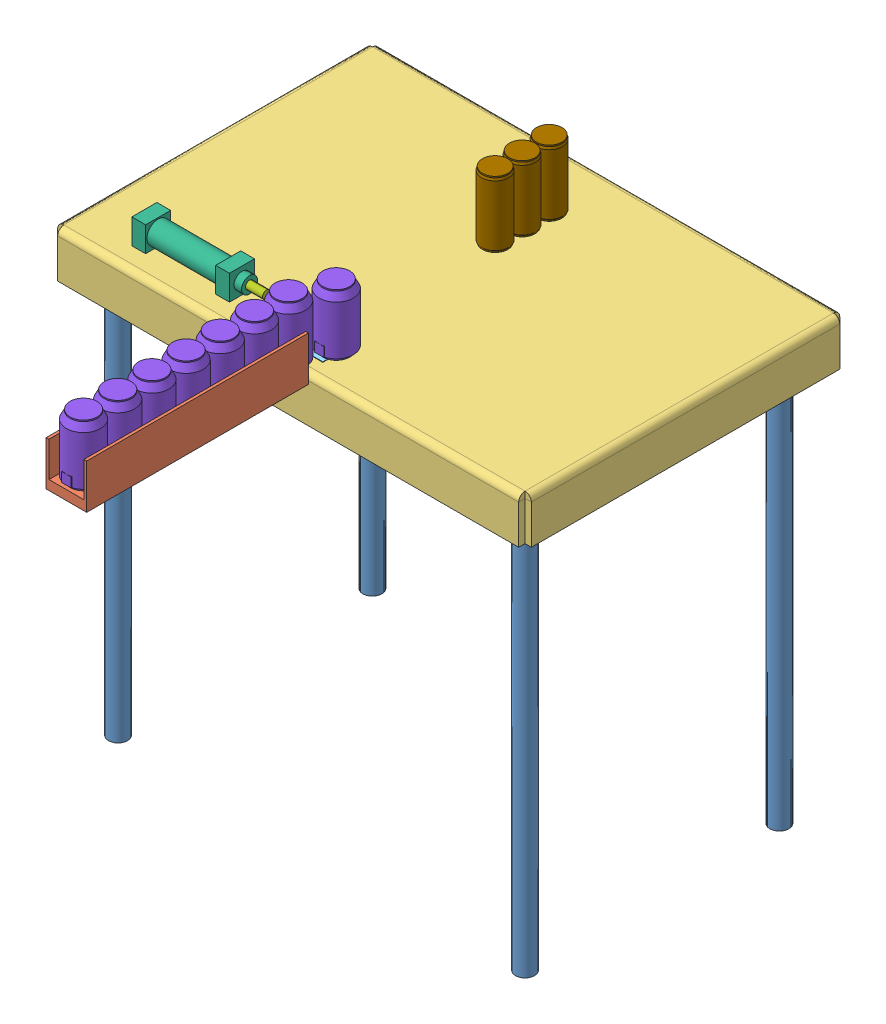
SolidWorks assembly Full_Assembly_v5, configuration Default. Lengths in mm.
Overall size (946.15 1065.21 1084.08).
19 component instances, 9 part files, 59 mates.
Components (placement in the parent):
- M37 Metal Table-1: M37 Metal Table [Default] at (-122.75 340.8931 1031.9817) size (914.4 863.6 609.6)
- Goose Output-1: Goose Output [Default] at (293.9688 417.0931 1047.8567) size (80.96 88.9 442.73)
- Table Topper-1: Table Topper [Default] at (-125.925 345.3431 1035.1567) size (946.15 90.8 641.35)
- Load Cell Assembly-1: Load Cell Assembly [Default] at (309.0555 378.227 899.7114) size (69.85 26.2 103.99)
  - Load Cell and Brace-1: Load Cell and Brace [Default] at (-9.1055 31.7162 92.7424) size (69 14.2 83)
  - scalePlate_v2_234-1: scalePlate_v2_234 [Default] at (-9.5305 57.9162 113.7283) x (0 0 -1) z (-1 0 0) size (69.85 12 69.85)
- Cylinder-1: Cylinder [Default] at (-22.0508 486.1431 953.5147) x (0 0 1) z (1 0 0) size (50 50 210)
- Rod-1: Rod [Default] at (221.9492 461.1431 978.5147) x (0 0.637822 -0.770184) z (0 0.770184 0.637822) size (16 134 16)
- can355mL-1: can355mL [Default] at (334.45 436.1431 1115.1477) x (0 0 -1) z (1 0 0) size (68.26 122.24 68.26)
- can355mL-2: can355mL [Default] at (334.45 436.1431 1251.6727) x (0 0 -1) z (1 0 0) size (68.26 122.24 68.26)
- can355mL-3: can355mL [Default] at (334.45 436.1431 1183.4102) x (0 0 -1) z (1 0 0) size (68.26 122.24 68.26)
- can250mL-1: can250mL [Default] at (334.45 436.1431 634.4892) x (0.234731 0 0.97206) z (-0.97206 0 0.234731) size (53.98 131.76 53.98)
- can250mL-2: can250mL [Default] at (334.45 436.1431 580.5142) x (0.907124 0 -0.420864) z (0.420864 0 0.907124) size (53.98 131.76 53.98)
- can250mL-3: can250mL [Default] at (334.45 436.1431 526.5392) x (0.515444 0 0.856923) z (-0.856923 0 0.515444) size (53.98 131.76 53.98)
- can355mL-7: can355mL [Default] at (334.45 436.1431 1046.8852) x (0 0 -1) z (1 0 0) size (68.26 122.24 68.26)
- can355mL-8: can355mL [Default] at (334.45 436.1431 1456.4602) x (0 0 -1) z (1 0 0) size (68.26 122.24 68.26)
- can355mL-9: can355mL [Default] at (334.45 436.1431 1319.9352) x (0 0 -1) z (1 0 0) size (68.26 122.24 68.26)
- can355mL-10: can355mL [Default] at (334.45 436.1431 1388.1977) x (0 0 -1) z (1 0 0) size (68.26 122.24 68.26)
- can355mL-11: can355mL [Default] at (361.1963 436.1431 978.5147) x (0 0 -1) z (1 0 0) size (68.26 122.24 68.26)
Mates (geometry in assembly coordinates):
- Width1: width aligned: plane of M37 Metal Table-1 through (791.65 366.2931 1031.9817) normal (1 0 0); plane of Table Topper-1 through (-122.75 366.2931 1031.9817) normal (-1 0 0); plane of M37 Metal Table-1 through (807.525 423.4431 1035.1567) normal (1 0 0); plane of Table Topper-1 through (-138.625 423.4431 1035.1567) normal (-1 0 0)
- Width2: width aligned: plane of M37 Metal Table-1 through (-122.75 366.2931 1031.9817) normal (0 0 1); plane of Table Topper-1 through (-122.75 366.2931 422.3817) normal (0 0 -1); plane of M37 Metal Table-1 through (-125.925 423.4431 1047.8567) normal (0 0 1); plane of Table Topper-1 through (-125.925 423.4431 406.5067) normal (0 0 -1)
- Distance1: distance = 863.6 mm aligned: plane of M37 Metal Table-1 through (-122.75 -446.5069 1031.9817) normal (0 -1 0); plane of Goose Output-1 through (374.9313 417.0931 1490.5914) normal (0 -1 0)
- LimitDistance1: limit distance = 432.5938 mm aligned: plane of Goose Output-1 through (374.9313 505.9931 1490.5914) normal (1 0 0); plane of Table Topper-1 through (807.525 423.4431 1035.1567) normal (1 0 0)
- LimitDistance2: limit distance = 432.5938 mm aligned: plane of Table Topper-1 through (-138.625 423.4431 1035.1567) normal (-1 0 0); plane of Goose Output-1 through (293.9688 417.0931 1490.5914) normal (-1 0 0)
- Parallel1: parallel aligned: plane of Goose Output-1 through (299.525 436.1431 1490.5914) normal (0 1 0); plane of Table Topper-1 through (-125.925 436.1431 1035.1567) normal (0 1 0)
- Coincident5: coincident aligned: plane of Goose Output-1 through (299.525 436.1431 1490.5914) normal (0 1 0); plane of Table Topper-1 through (-125.925 436.1431 1035.1567) normal (0 1 0)
- Coincident7: coincident aligned: plane of Table Topper-1 through (-125.925 436.1431 1035.1567) normal (0 1 0); plane of Load Cell Assembly-1/scalePlate_v2_234-1 through (299.525 436.1431 1013.4397) normal (0 1 0)
- Concentric1: concentric anti-aligned: cylinder of Cylinder-1 through (187.9492 461.1431 978.5147) axis (-1 0 0) radius 16; cylinder of Rod-1 through (87.9492 461.1431 978.5147) axis (1 0 0) radius 8
- LimitDistance3: limit distance = 34 mm aligned: plane of Rod-1 through (221.9492 461.1431 978.5147) normal (1 0 0); plane of Cylinder-1 through (187.9492 461.1431 978.5147) normal (1 0 0)
- Parallel2: parallel anti-aligned: plane of Table Topper-1 through (-125.925 423.4431 1047.8567) normal (0 0 1); plane of Cylinder-1 through (172.9492 486.1431 953.5147) normal (0 0 -1)
- Coincident9: coincident anti-aligned: plane of Table Topper-1 through (-125.925 436.1431 1035.1567) normal (0 1 0); plane of Cylinder-1 through (5.4492 436.1431 953.5147) normal (0 -1 0)
- Width3: width anti-aligned: plane of Goose Output-1 through (374.9313 505.9931 1490.5914) normal (1 0 0); plane of Load Cell Assembly-1/scalePlate_v2_234-1 through (293.9688 417.0931 1490.5914) normal (-1 0 0); plane of Goose Output-1 through (299.525 432.1431 1013.4397) normal (-1 0 0); plane of Load Cell Assembly-1/scalePlate_v2_234-1 through (369.375 432.1431 1013.4397) normal (1 0 0)
- Width4: width anti-aligned: plane of Cylinder-1 through (172.9492 486.1431 953.5147) normal (0 0 -1); plane of Load Cell Assembly-1/scalePlate_v2_234-1 through (172.9492 486.1431 1003.5147) normal (0 0 1); plane of Cylinder-1 through (299.525 432.1431 1013.4397) normal (0 0 1); plane of Load Cell Assembly-1/scalePlate_v2_234-1 through (299.525 432.1431 943.5897) normal (0 0 -1)
- Width5: width anti-aligned: plane of Table Topper-1 through (807.525 423.4431 1035.1567) normal (1 0 0); plane of Load Cell Assembly-1/scalePlate_v2_234-1 through (-138.625 423.4431 1035.1567) normal (-1 0 0); plane of Table Topper-1 through (299.525 432.1431 1013.4397) normal (-1 0 0); plane of Load Cell Assembly-1/scalePlate_v2_234-1 through (369.375 432.1431 1013.4397) normal (1 0 0)
- Coincident11: coincident anti-aligned: plane of Table Topper-1 through (-125.925 436.1431 1035.1567) normal (0 1 0); plane of can250mL-1 through (340.4122 436.1431 659.1796) normal (0 -1 0)
- Coincident18: coincident anti-aligned: plane of Table Topper-1 through (-125.925 436.1431 1035.1567) normal (0 1 0); plane of can355mL-2 through (334.45 436.1431 1224.6852) normal (0 -1 0)
- Coincident19: coincident anti-aligned: plane of Table Topper-1 through (-125.925 436.1431 1035.1567) normal (0 1 0); plane of can355mL-3 through (334.45 436.1431 1156.4227) normal (0 -1 0)
- Tangent5: tangent anti-aligned: cylinder of can355mL-2 through (334.45 436.1431 1251.6727) axis (0 -1 0) radius 34.1313; cylinder of can355mL-3 through (334.45 436.1431 1183.4102) axis (0 -1 0) radius 34.1313
- Width6: width: plane of Goose Output-1 through (299.525 505.9931 1490.5914) normal (1 0 0); plane of can250mL-1 through (369.375 436.1431 1490.5914) normal (-1 0 0); cylinder of Goose Output-1 through (334.45 436.1431 634.4892) axis (0 -1 0) radius 26.9875
- Width8: width: plane of Goose Output-1 through (369.375 436.1431 1490.5914) normal (-1 0 0); plane of can355mL-2 through (299.525 505.9931 1490.5914) normal (1 0 0); cylinder of Goose Output-1 through (334.45 436.1431 1251.6727) axis (0 -1 0) radius 34.1313
- Width10: width: plane of Goose Output-1 through (299.525 505.9931 1490.5914) normal (1 0 0); plane of can355mL-3 through (369.375 436.1431 1490.5914) normal (-1 0 0); cylinder of Goose Output-1 through (334.45 436.1431 1183.4102) axis (0 -1 0) radius 34.1313
- Coincident20: coincident anti-aligned: plane of Table Topper-1 through (-125.925 436.1431 1035.1567) normal (0 1 0); plane of can250mL-2 through (357.491 436.1431 569.8243) normal (0 -1 0)
- Coincident21: coincident anti-aligned: plane of Table Topper-1 through (-125.925 436.1431 1035.1567) normal (0 1 0); plane of can250mL-3 through (347.5423 436.1431 548.3051) normal (0 -1 0)
- Tangent6: tangent anti-aligned: cylinder of can250mL-1 through (334.45 436.1431 634.4892) axis (0 -1 0) radius 26.9875; cylinder of can250mL-2 through (334.45 436.1431 580.5142) axis (0 -1 0) radius 26.9875
- Tangent7: tangent anti-aligned: cylinder of can250mL-2 through (334.45 436.1431 580.5142) axis (0 -1 0) radius 26.9875; cylinder of can250mL-3 through (334.45 436.1431 526.5392) axis (0 -1 0) radius 26.9875
- Width11: width: plane of Goose Output-1 through (299.525 505.9931 1490.5914) normal (1 0 0); plane of can250mL-2 through (369.375 436.1431 1490.5914) normal (-1 0 0); cylinder of Goose Output-1 through (334.45 436.1431 580.5142) axis (0 -1 0) radius 26.9875
- Width12: width: plane of Goose Output-1 through (299.525 505.9931 1490.5914) normal (1 0 0); plane of can250mL-3 through (369.375 436.1431 1490.5914) normal (-1 0 0); cylinder of Goose Output-1 through (334.45 436.1431 526.5392) axis (0 -1 0) radius 26.9875
- Coincident22: coincident anti-aligned: plane of Goose Output-1 through (293.9688 417.0931 1047.8567) normal (0 0 -1); plane of Table Topper-1 through (-125.925 423.4431 1047.8567) normal (0 0 1)
- Width14: width aligned: plane of Table Topper-1 through (370.391 345.3431 1014.4557) normal (-1 0 0); plane of Table Topper-1 through (298.509 345.3431 1014.4557) normal (1 0 0); plane of Load Cell Assembly-1/scalePlate_v2_234-1 through (299.525 432.1431 1013.4397) normal (-1 0 0); plane of Load Cell Assembly-1/scalePlate_v2_234-1 through (369.375 432.1431 1013.4397) normal (1 0 0)
- Width15: width anti-aligned: plane of Table Topper-1 through (298.509 345.3431 1014.4557) normal (0 0 -1); plane of Table Topper-1 through (298.509 345.3431 942.5737) normal (0 0 1); plane of Load Cell Assembly-1/scalePlate_v2_234-1 through (299.525 432.1431 1013.4397) normal (0 0 1); plane of Load Cell Assembly-1/scalePlate_v2_234-1 through (299.525 432.1431 943.5897) normal (0 0 -1)
- Width17: width: plane of Goose Output-1 through (369.375 436.1431 1490.5914) normal (-1 0 0); plane of Goose Output-1 through (299.525 505.9931 1490.5914) normal (1 0 0); cylinder of can355mL-4 through (334.45 436.1431 1259.8293) axis (0 -1 0) radius 34.1313
- Coincident31: coincident anti-aligned: plane of Table Topper-1 through (-125.925 436.1431 1035.1567) normal (0 1 0); plane of can355mL-7 through (334.45 436.1431 1019.8977) normal (0 -1 0)
- Width19: width: plane of Goose Output-1 through (369.375 436.1431 1490.5914) normal (-1 0 0); plane of Goose Output-1 through (299.525 505.9931 1490.5914) normal (1 0 0); cylinder of can355mL-7 through (334.45 436.1431 1046.8852) axis (0 -1 0) radius 34.1313
- Coincident33: coincident anti-aligned: plane of Table Topper-1 through (-125.925 436.1431 1035.1567) normal (0 1 0); plane of can355mL-1 through (334.45 436.1431 1088.1602) normal (0 -1 0)
- Tangent13: tangent anti-aligned: cylinder of can355mL-1 through (334.45 436.1431 1115.1477) axis (0 -1 0) radius 34.1313; cylinder of can355mL-3 through (334.45 436.1431 1183.4102) axis (0 -1 0) radius 34.1313
- Width20: width: plane of Goose Output-1 through (299.525 505.9931 1490.5914) normal (1 0 0); plane of Goose Output-1 through (369.375 436.1431 1490.5914) normal (-1 0 0); cylinder of can355mL-1 through (334.45 436.1431 1115.1477) axis (0 -1 0) radius 34.1313
- Parallel4: parallel aligned: plane of M37 Metal Table-1 through (-122.75 366.2931 1031.9817) normal (0 0 1); plane of can355mL-7 through (334.45 436.1431 1081.0164) normal (0 0 1)
- Parallel5: parallel aligned: plane of M37 Metal Table-1 through (-122.75 366.2931 1031.9817) normal (0 0 1); plane of can355mL-2 through (334.45 436.1431 1285.8039) normal (0 0 1)
- Parallel6: parallel aligned: plane of M37 Metal Table-1 through (-122.75 366.2931 1031.9817) normal (0 0 1); plane of can355mL-3 through (334.45 436.1431 1217.5414) normal (0 0 1)
- Parallel7: parallel aligned: plane of M37 Metal Table-1 through (-122.75 366.2931 1031.9817) normal (0 0 1); plane of can355mL-1 through (334.45 436.1431 1149.2789) normal (0 0 1)
- LimitDistance14: limit distance = 68.2625 mm aligned: plane of can355mL-7 through (334.45 436.1431 1081.0164) normal (0 0 1); plane of can355mL-1 through (334.45 436.1431 1149.2789) normal (0 0 1)
- Tangent14: tangent anti-aligned: cylinder of can355mL-9 through (334.45 436.1431 1319.9352) axis (0 -1 0) radius 34.1313; cylinder of can355mL-10 through (334.45 436.1431 1388.1977) axis (0 -1 0) radius 34.1313
- Tangent15: tangent anti-aligned: cylinder of can355mL-8 through (334.45 436.1431 1456.4602) axis (0 -1 0) radius 34.1313; cylinder of can355mL-10 through (334.45 436.1431 1388.1977) axis (0 -1 0) radius 34.1313
- Coincident38: coincident anti-aligned: plane of Table Topper-1 through (-125.925 436.1431 1035.1567) normal (0 1 0); plane of can355mL-8 through (334.45 436.1431 1429.4727) normal (0 -1 0)
- Coincident39: coincident aligned: plane of can355mL-9 through (334.45 436.1431 1292.9477) normal (0 -1 0); plane of can355mL-10 through (334.45 436.1431 1361.2102) normal (0 -1 0)
- Coincident40: coincident anti-aligned: plane of Table Topper-1 through (-125.925 436.1431 1035.1567) normal (0 1 0); plane of can355mL-10 through (334.45 436.1431 1361.2102) normal (0 -1 0)
- Width21: width: plane of Goose Output-1 through (299.525 505.9931 1490.5914) normal (1 0 0); plane of can355mL-8 through (369.375 436.1431 1490.5914) normal (-1 0 0); cylinder of Goose Output-1 through (334.45 436.1431 1456.4602) axis (0 -1 0) radius 34.1313
- Width22: width: plane of Goose Output-1 through (374.9313 505.9931 1490.5914) normal (1 0 0); plane of can355mL-10 through (293.9688 417.0931 1490.5914) normal (-1 0 0); cylinder of Goose Output-1 through (334.45 436.1431 1388.1977) axis (0 -1 0) radius 34.1313
- Width23: width: plane of Goose Output-1 through (374.9313 505.9931 1490.5914) normal (1 0 0); plane of can355mL-9 through (293.9688 417.0931 1490.5914) normal (-1 0 0); cylinder of Goose Output-1 through (334.45 436.1431 1319.9352) axis (0 -1 0) radius 34.1313
- LimitDistance15: limit distance = 68.2625 mm aligned: plane of can355mL-9 through (334.45 436.1431 1354.0664) normal (0 0 1); plane of can355mL-2 through (334.45 436.1431 1285.8039) normal (0 0 1)
- Parallel8: parallel aligned: plane of M37 Metal Table-1 through (-122.75 366.2931 1031.9817) normal (0 0 1); plane of can355mL-8 through (334.45 436.1431 1490.5914) normal (0 0 1)
- Parallel10: parallel aligned: plane of M37 Metal Table-1 through (-122.75 366.2931 1031.9817) normal (0 0 1); plane of can355mL-10 through (334.45 436.1431 1422.3289) normal (0 0 1)
- LimitDistance16: limit distance = 0 mm aligned: plane of can355mL-8 through (334.45 436.1431 1490.5914) normal (0 0 1); plane of Goose Output-1 through (293.9688 417.0931 1490.5914) normal (0 0 1)
- Parallel12: parallel aligned: plane of M37 Metal Table-1 through (-122.75 366.2931 1031.9817) normal (0 0 1); plane of can355mL-11 through (361.1963 436.1431 1012.646) normal (0 0 1)
- LimitDistance18: limit distance = 68.3705 mm aligned: plane of can355mL-11 through (361.1963 436.1431 1012.646) normal (0 0 1); plane of can355mL-7 through (334.45 436.1431 1081.0164) normal (0 0 1)
- PathMate3: path: point of can355mL-11
- Parallel13: parallel anti-aligned: plane of Table Topper-1 through (-125.925 436.1431 1035.1567) normal (0 1 0); plane of can355mL-11 through (361.1963 436.1431 951.5272) normal (0 -1 0)
- Parallel14: parallel aligned: plane of M37 Metal Table-1 through (-122.75 366.2931 1031.9817) normal (0 0 1); plane of can355mL-11 through (361.1963 436.1431 1012.646) normal (0 0 1)
